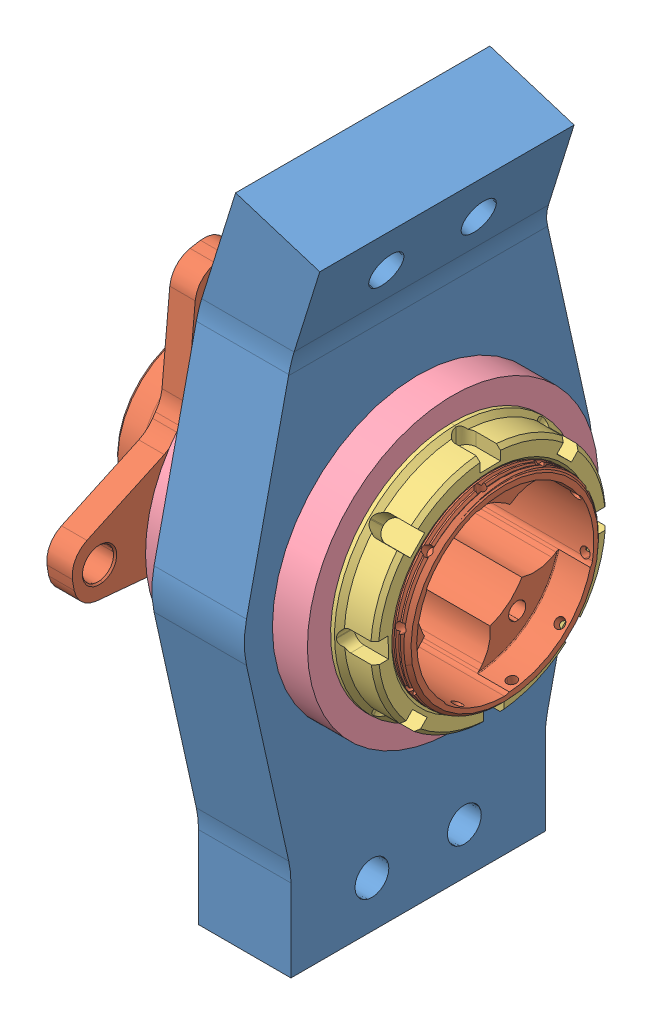
SolidWorks assembly Rear Wheel Assembly, configuration Default. Lengths in mm.
Overall size (101.92 211.1 136.73).
5 component instances, 4 part files, 8 mates.
Components (placement in the parent):
- WheelKnuckle_Back-1: WheelKnuckle_Back [Default] at origin size (38.73 211.1 136.73)
- D5580.step-1: D5580.step [Default] at (43.1025 0 0) x (-1 0 0) z (0 0.985491 0.169729) size (101.92 117.35 117.35)
- D5239.step-1: D5239.step [Default] at (38.975 0 0) x (-1 0 0) z (0 -0.999879 -0.015564) size (12.7 79.38 79.38)
- Rear Ball Bearing (L610549)-1: Rear Ball Bearing (L610549) [Default] at (16.75 0 0) x (1 0 0) z (0 0.227438 0.973792) size (19.05 94.42 94.42)
- Rear Ball Bearing (L610549)-2: Rear Ball Bearing (L610549) [Default] at (-16.75 0 0) x (1 0 0) z (0 0.227438 0.973792) size (19.05 94.42 94.42)
Mates (geometry in assembly coordinates):
- Concentric1: concentric aligned: cylinder of WheelKnuckle_Back-1 through (-15 0 0) axis (1 0 0) radius 47.3122; cylinder of D5580.step-1 through (43.1025 0 0) axis (1 0 0) radius 31.75
- Coincident1: coincident anti-aligned: plane of WheelKnuckle_Back-1 through (-15 0 0) normal (-1 0 0); plane of D5580.step-1 through (-15 -5.6476 32.7912) normal (1 0 0)
- Screw1: screw = 1 aligned: cylinder of D5580.step-1 through (43.1025 0 0) axis (1 0 0) radius 31.6865; cylinder of D5239.step-1 through (38.975 0 0) axis (1 0 0) radius 31.242
- Tangent1: tangent anti-aligned: cylinder of D5580.step-1 through (40.5625 34.4497 -65.417) axis (0 -0.465955 0.884808) radius 1.5875; plane of D5239.step-1 through (38.975 0.506 -32.5081) normal (1 0 0)
- Concentric2: concentric anti-aligned: cylinder of D5580.step-1 through (43.1025 0 0) axis (1 0 0) radius 31.75; cylinder of Rear Ball Bearing (L610549)-1 through (26.275 0 0) axis (-1 0 0) radius 47.2122
- Coincident2: coincident anti-aligned: plane of D5239.step-1 through (26.275 0.6177 -39.6827) normal (-1 0 0); plane of Rear Ball Bearing (L610549)-1 through (26.275 0 0) normal (1 0 0)
- Concentric3: concentric anti-aligned: cylinder of D5580.step-1 through (43.1025 0 0) axis (1 0 0) radius 31.75; cylinder of Rear Ball Bearing (L610549)-2 through (-7.225 0 0) axis (-1 0 0) radius 31.75
- Width1: width anti-aligned: plane of Rear Ball Bearing (L610549)-1 through (26.275 0 0) normal (1 0 0); plane of Rear Ball Bearing (L610549)-2 through (-26.275 0 0) normal (-1 0 0); plane of WheelKnuckle_Back-1 through (-15 0 0) normal (-1 0 0); plane of WheelKnuckle_Back-1 through (15 0 0) normal (1 0 0)
